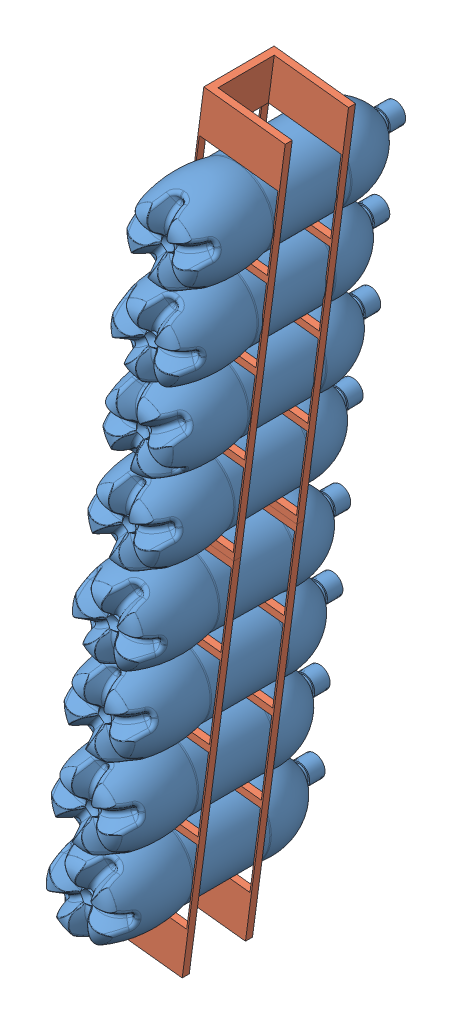
SolidWorks assembly bottle rack, configuration Default. Lengths in mm.
Overall size (263.26 1090.64 368.59).
10 component instances, 2 part files, 24 mates.
Components (placement in the parent):
- modified bottle-1: modified bottle [Default] at (160.3893 1086.8063 95.8399) x (0.740919 -0.671588 -0.002908) z (0.671486 0.74087 -0.014756) size (119.84 349.32 119.84)
- modified bottle-2: modified bottle [Default] at (161.3395 1170.7685 98.7507) x (0.999378 -0.033256 -0.011759) z (0.033146 0.999407 -0.009376) size (119.84 349.32 119.84)
- modified bottle-3: modified bottle [Default] at (264.91 1330.7284 88.9112) x (-0.630622 -0.775954 0.014578) z (0.775997 -0.630726 -0.003698) size (119.84 349.32 119.84)
- modified bottle-4: modified bottle [Default] at (238.1247 910.5654 99.3269) x (-0.929887 0.36702 0.024624) z (-0.366686 -0.930188 0.01708) size (119.84 349.32 119.84)
- BALL STANDF-1: BALL STANDF [Default] at (289.7246 1335.9787 -17.4025) x (-0.012064 -0.00898 -0.999887) z (-0.992318 0.123237 0.010866) size (100 542.12 114)
- BALL STANDF-2: BALL STANDF [Default] at (170.1923 380.5426 -97.3896) x (0.012064 0.00898 0.999887) z (-0.992318 0.123237 0.010866) size (100 542.12 114)
- modified bottle-5: modified bottle [Default] at (206.0868 663.8041 101.77) x (-0.937975 0.346605 0.008204) z (-0.346492 -0.937968 0.012605) size (119.84 349.32 119.84)
- modified bottle-6: modified bottle [Default] at (190.9037 543.6105 105.0126) x (-0.930121 0.367167 0.007925) z (-0.367055 -0.930112 0.012782) size (119.84 349.32 119.84)
- modified bottle-7: modified bottle [Default] at (209.5496 766.6505 105.9993) x (-0.725664 0.68798 -0.009781) z (-0.687894 -0.725125 0.031566) size (119.84 349.32 119.84)
- modified bottle-8: modified bottle [Default] at (116.104 498.9398 97.2641) x (0.159251 -0.987214 0.006945) z (0.987164 0.15915 -0.01334) size (119.84 349.32 119.84)
Mates (geometry in assembly coordinates):
- Tangent5: tangent anti-aligned: cylinder of modified bottle-1 through (197.1588 1046.9056 -234.2827) axis (-0.012064 -0.00898 -0.999887) radius 55; plane of BALL STANDF-1 through (246.5076 987.6685 -13.7529) normal (0.123125 0.992337 -0.010398)
- Tangent7: tangent anti-aligned: cylinder of modified bottle-2 through (212.3242 1165.976 -231.8588) axis (-0.012064 -0.00898 -0.999887) radius 55; plane of BALL STANDF-1 through (261.2827 1106.7489 -15.0006) normal (0.123125 0.992337 -0.010398)
- Tangent8: tangent anti-aligned: cylinder of modified bottle-3 through (226.2447 1285.0876 -240.2497) axis (-0.012064 -0.00898 -0.999887) radius 55; plane of BALL STANDF-1 through (276.0577 1225.8293 -16.2483) normal (0.123125 0.992337 -0.010398)
- Tangent11: tangent anti-aligned: cylinder of modified bottle-4 through (177.3536 928.4898 -229.1705) axis (-0.029174 -0.006854 -0.999551) radius 55; plane of BALL STANDF-1 through (231.7326 868.5881 -12.5051) normal (0.123125 0.992337 -0.010398)
- Lock1: lock: unknown of modified bottle-3; unknown of BALL STANDF-1
- Lock2: lock: unknown of modified bottle-2; unknown of BALL STANDF-1
- Lock3: lock: unknown of modified bottle-1; unknown of BALL STANDF-1
- Lock4: lock: unknown of modified bottle-4; unknown of BALL STANDF-1
- Coincident1: coincident anti-aligned: plane of BALL STANDF-1 through (230.5013 858.6648 -12.4011) normal (-0.123125 -0.992337 0.010398); plane of BALL STANDF-2 through (229.4156 857.8566 -102.391) normal (0.123125 0.992337 -0.010398)
- Coincident2: coincident anti-aligned: plane of BALL STANDF-1 through (230.5013 858.6648 -12.4011) normal (-0.123125 -0.992337 0.010398); plane of BALL STANDF-2 through (229.4156 857.8566 -102.391) normal (0.123125 0.992337 -0.010398)
- Coincident3: coincident aligned: plane of BALL STANDF-1 through (178.585 1349.7812 -16.1855) normal (-0.992318 0.123237 0.010866); plane of BALL STANDF-2 through (59.0527 394.3452 -96.1726) normal (-0.992318 0.123237 0.010866)
- Coincident4: coincident aligned: plane of BALL STANDF-1 through (288.5786 1335.1256 -112.3917) normal (-0.012064 -0.00898 -0.999887); plane of BALL STANDF-2 through (58.8692 393.3079 -101.1617) normal (-0.012064 -0.00898 -0.999887)
- Tangent21: tangent: line of BALL STANDF-2 through (229.2098 848.6965 -17.2966) axis (-0.992318 0.123237 0.010866); cylinder of modified bottle-7 through (164.812 794.71 -224.3584) axis (-0.014624 -0.029634 -0.999454) radius 55
- Tangent22: tangent anti-aligned: plane of BALL STANDF-2 through (121.4067 872.2657 -6.2065) normal (0.992318 -0.123237 -0.010866); cylinder of modified bottle-7 through (164.812 794.71 -224.3584) axis (-0.014624 -0.029634 -0.999454) radius 55
- Tangent23: tangent anti-aligned: plane of BALL STANDF-2 through (213.4093 728.8528 -101.0393) normal (-0.123125 -0.992337 0.010398); cylinder of modified bottle-5 through (150.5171 679.9039 -227.7414) axis (-0.012064 -0.00898 -0.999887) radius 55
- Tangent24: tangent anti-aligned: plane of BALL STANDF-2 through (121.4067 872.2657 -6.2065) normal (0.992318 -0.123237 -0.010866); cylinder of modified bottle-5 through (150.5171 679.9039 -227.7414) axis (-0.012064 -0.00898 -0.999887) radius 55
- Tangent25: tangent anti-aligned: plane of BALL STANDF-2 through (198.6342 609.7724 -99.7915) normal (-0.123125 -0.992337 0.010398); cylinder of modified bottle-6 through (135.7659 560.8413 -224.5142) axis (-0.012064 -0.00898 -0.999887) radius 55
- Tangent29: tangent anti-aligned: plane of BALL STANDF-2 through (198.6342 609.7724 -99.7915) normal (-0.123125 -0.992337 0.010398); cylinder of modified bottle-6 through (135.7659 560.8413 -224.5142) axis (-0.012064 -0.00898 -0.999887) radius 55
- Tangent30: tangent anti-aligned: plane of BALL STANDF-2 through (229.4299 857.9719 -102.3922) normal (-0.992318 0.123237 0.010866); cylinder of modified bottle-6 through (135.7659 560.8413 -224.5142) axis (-0.012064 -0.00898 -0.999887) radius 55
- Tangent33: tangent anti-aligned: plane of BALL STANDF-2 through (229.4299 857.9719 -102.3922) normal (-0.992318 0.123237 0.010866); cylinder of modified bottle-8 through (120.8817 441.6796 -232.3166) axis (-0.012064 -0.00898 -0.999887) radius 55
- Tangent34: tangent anti-aligned: plane of BALL STANDF-2 through (183.8592 490.692 -98.5438) normal (-0.123125 -0.992337 0.010398); cylinder of modified bottle-8 through (120.8817 441.6796 -232.3166) axis (-0.012064 -0.00898 -0.999887) radius 55
- Lock5: lock: unknown of BALL STANDF-2; unknown of modified bottle-8
- Lock6: lock: unknown of BALL STANDF-2; unknown of modified bottle-6
- Lock7: lock: unknown of BALL STANDF-2; unknown of modified bottle-7
